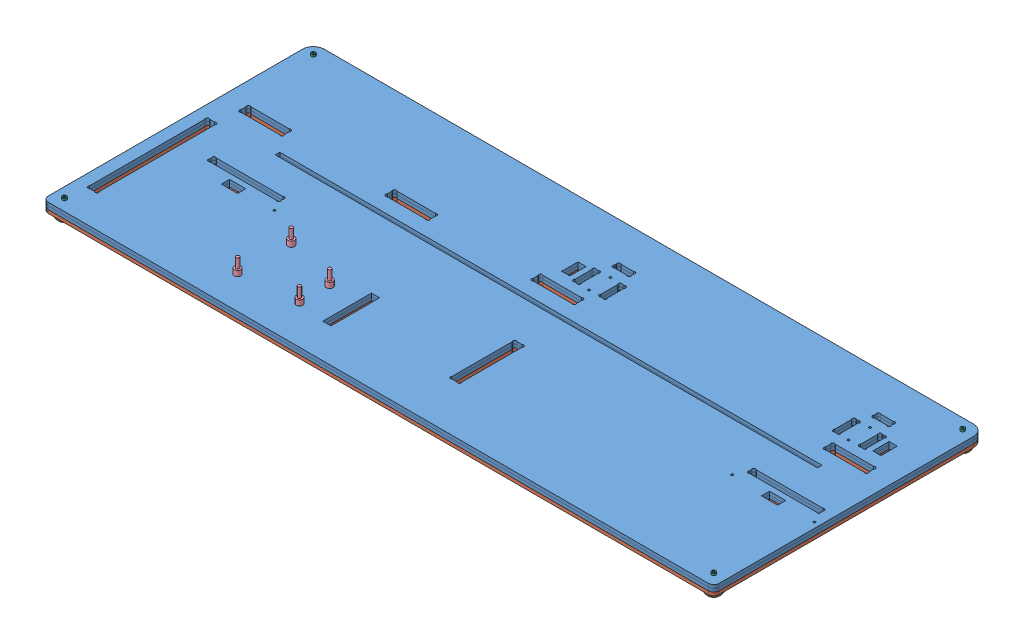
SolidWorks assembly socle-complet, configuration Défaut. Lengths in mm.
Overall size (621.62 30.74 251.62).
19 component instances, 6 part files, 46 mates.
Components (placement in the parent):
- socle-1-1: socle-1 [Défaut] at (-302.5453 40.1785 745) size (620 3 250)
- socle-1-2: socle-1 [Défaut] at (-302.5453 37.1785 745) size (620 3 250)
- socle-2-3: socle-2 [Défaut] at (-302.5453 34.1785 745) size (620 3 250)
- socle-patin-ecrou_m2-1: socle-patin-ecrou_m2 [Défaut] at (-292.5453 34.1785 735) x (0.367083 0 0.930188) z (-0.930188 0 0.367083) size (16 7.74 16)
- socle-patin-ecrou_m2-2: socle-patin-ecrou_m2 [Défaut] at (-292.5453 34.1785 505) x (-0.622025 0 0.782997) z (-0.782997 0 -0.622025) size (16 7.74 16)
- socle-patin-ecrou_m2-3: socle-patin-ecrou_m2 [Défaut] at (307.4547 34.1785 505) x (0.367083 0 0.930188) z (-0.930188 0 0.367083) size (16 7.74 16)
- socle-patin-ecrou_m2-4: socle-patin-ecrou_m2 [Défaut] at (307.4547 34.1785 735) x (0.367083 0 0.930188) z (-0.930188 0 0.367083) size (16 7.74 16)
- socle-carte_pied-1: socle-carte_pied [Défaut] at (-152.5453 38.1785 715) x (0 1 0) z (-0.920347 0 -0.391102) size (19 6 6)
- socle-carte_pied-2: socle-carte_pied [Défaut] at (-151.2753 38.1785 666.74) x (0 1 0) z (-0.842592 0 -0.538553) size (19 6 6)
- socle-carte_pied-3: socle-carte_pied [Défaut] at (-100.4753 38.1785 681.98) x (0 1 0) z (-0.819102 0 -0.573647) size (19 6 6)
- socle-carte_pied-4: socle-carte_pied [Défaut] at (-100.4753 38.1785 709.92) x (0 1 0) z (0.984574 0 0.174968) size (19 6 6)
- ecrou-h-1: ecrou-h [6007 HU M2] at (-292.5453 31.1785 735) size (4 1.6 4.62)
- vis-chc-1: vis-chc [Vis CHC M2x16] at (-292.5453 43.1785 735) x (0.999999 0 -0.001395) z (0.001395 0 0.999999) size (3.8 18 3.8)
- vis-chc-2: vis-chc [Vis CHC M2x16] at (307.4547 43.1785 735) x (0.999999 0 -0.001395) z (0.001395 0 0.999999) size (3.8 18 3.8)
- vis-chc-3: vis-chc [Vis CHC M2x16] at (-292.5453 43.1785 505) x (0.610012 0 -0.792392) z (0.792392 0 0.610012) size (3.8 18 3.8)
- vis-chc-4: vis-chc [Vis CHC M2x16] at (307.4547 43.1785 505) x (0.999999 0 -0.001395) z (0.001395 0 0.999999) size (3.8 18 3.8)
- ecrou-h-2: ecrou-h [6007 HU M2] at (307.4547 31.1785 735) size (4 1.6 4.62)
- ecrou-h-3: ecrou-h [6007 HU M2] at (307.4547 31.1785 505) size (4 1.6 4.62)
- ecrou-h-4: ecrou-h [6007 HU M2] at (-292.5453 31.1785 505) size (4 1.6 4.62)
Mates (geometry in assembly coordinates):
- Coïncidente1: coincident anti-aligned: plane of socle-1 through (-292.5453 40.1785 505) normal (0 -1 0); plane of socle-2 through (-292.5453 40.1785 505) normal (0 1 0)
- Coïncidente2: coincident aligned: plane of socle-1 through (-302.5453 43.1785 745) normal (0 0 1); plane of socle-2 through (-302.5453 40.1785 745) normal (0 0 1)
- Coïncidente3: coincident aligned: plane of socle-1 through (-302.5453 43.1785 505) normal (-1 0 0); plane of socle-2 through (-302.5453 40.1785 505) normal (-1 0 0)
- Coïncidente4: coincident anti-aligned: plane of socle-2 through (-292.5453 37.1785 505) normal (0 -1 0); plane of socle-3 through (-292.5453 37.1785 505) normal (0 1 0)
- Coïncidente5: coincident aligned: plane of socle-2 through (-302.5453 40.1785 745) normal (0 0 1); plane of socle-3 through (-302.5453 37.1785 745) normal (0 0 1)
- Coïncidente6: coincident aligned: plane of socle-2 through (-302.5453 40.1785 505) normal (-1 0 0); plane of socle-3 through (-302.5453 37.1785 505) normal (-1 0 0)
- Coaxiale1: concentric anti-aligned: cylinder of socle-3 through (-292.5453 37.1785 735) axis (0 -1 0) radius 1; cylinder of socle-patin-ecrou_m2-1 through (-292.5453 26.1785 735) axis (0 1 0) radius 1
- Coïncidente7: coincident anti-aligned: plane of socle-3 through (-292.5453 34.1785 505) normal (0 -1 0); plane of socle-patin-ecrou_m2-1 through (-295.482 34.1785 727.5585) normal (0 1 0)
- Coaxiale2: concentric anti-aligned: cylinder of socle-3 through (307.4547 37.1785 735) axis (0 -1 0) radius 1; cylinder of socle-patin-ecrou_m2-4 through (307.4547 26.1785 735) axis (0 1 0) radius 1
- Coaxiale3: concentric anti-aligned: cylinder of socle-3 through (307.4547 37.1785 505) axis (0 -1 0) radius 1; cylinder of socle-patin-ecrou_m2-3 through (307.4547 26.1785 505) axis (0 1 0) radius 1
- Coaxiale4: concentric anti-aligned: cylinder of socle-3 through (-292.5453 37.1785 505) axis (0 -1 0) radius 1; cylinder of socle-patin-ecrou_m2-2 through (-292.5453 26.1785 505) axis (0 1 0) radius 1
- Coïncidente8: coincident anti-aligned: plane of socle-3 through (-292.5453 34.1785 505) normal (0 -1 0); plane of socle-patin-ecrou_m2-2 through (-287.5691 34.1785 498.736) normal (0 1 0)
- Coïncidente9: coincident anti-aligned: plane of socle-3 through (-292.5453 34.1785 505) normal (0 -1 0); plane of socle-patin-ecrou_m2-3 through (304.518 34.1785 497.5585) normal (0 1 0)
- Coïncidente10: coincident anti-aligned: plane of socle-3 through (-292.5453 34.1785 505) normal (0 -1 0); plane of socle-patin-ecrou_m2-4 through (304.518 34.1785 727.5585) normal (0 1 0)
- Parallèle1: parallel anti-aligned: plane of socle-3 through (317.4547 37.1785 505) normal (1 0 0); plane of socle-patin-ecrou_m2-4 through (309.4725 26.2413 736.165) normal (-1 0 0)
- Parallèle2: parallel anti-aligned: plane of socle-3 through (317.4547 37.1785 505) normal (1 0 0); plane of socle-patin-ecrou_m2-3 through (309.4725 26.2413 506.165) normal (-1 0 0)
- Parallèle3: parallel anti-aligned: plane of socle-3 through (-302.5453 37.1785 505) normal (-1 0 0); plane of socle-patin-ecrou_m2-1 through (-294.5631 26.2413 733.835) normal (1 0 0)
- Parallèle4: parallel anti-aligned: plane of socle-3 through (-302.5453 37.1785 505) normal (-1 0 0); plane of socle-patin-ecrou_m2-2 through (-294.5631 26.2413 503.835) normal (1 0 0)
- Coaxiale5: concentric aligned: cylinder of socle-1 through (-152.5453 40.1785 715) axis (0 1 0) radius 1.59; cylinder of socle-carte_pied-1 through (-152.5453 57.1785 715) axis (0 1 0) radius 1.5
- Coaxiale6: concentric aligned: cylinder of socle-1 through (-100.4753 40.1785 709.92) axis (0 1 0) radius 1.59; cylinder of socle-carte_pied-4 through (-100.4753 57.1785 709.92) axis (0 1 0) radius 1.5
- Coaxiale7: concentric aligned: cylinder of socle-1 through (-100.4753 40.1785 681.98) axis (0 1 0) radius 1.59; cylinder of socle-carte_pied-3 through (-100.4753 57.1785 681.98) axis (0 1 0) radius 1.5
- Coaxiale8: concentric aligned: cylinder of socle-1 through (-151.2753 40.1785 666.74) axis (0 1 0) radius 1.59; cylinder of socle-carte_pied-2 through (-151.2753 57.1785 666.74) axis (0 1 0) radius 1.5
- Coïncidente11: coincident anti-aligned: plane of socle-1 through (-292.5453 43.1785 505) normal (0 1 0); plane of socle-carte_pied-1 through (-151.9586 43.1785 713.6195) normal (0 -1 0)
- Coïncidente12: coincident anti-aligned: plane of socle-1 through (-292.5453 43.1785 505) normal (0 1 0); plane of socle-carte_pied-2 through (-150.4675 43.1785 665.4761) normal (0 -1 0)
- Coïncidente13: coincident anti-aligned: plane of socle-1 through (-292.5453 43.1785 505) normal (0 1 0); plane of socle-carte_pied-3 through (-99.6148 43.1785 680.7513) normal (0 -1 0)
- Coïncidente14: coincident anti-aligned: plane of socle-1 through (-292.5453 43.1785 505) normal (0 1 0); plane of socle-carte_pied-4 through (-100.7378 43.1785 711.3969) normal (0 -1 0)
- Coaxiale9: concentric anti-aligned: cylinder of socle-1-1 through (-292.5453 43.1785 735) axis (0 -1 0) radius 1; cylinder of vis-chc-1 through (-292.5453 27.1785 735) axis (0 1 0) radius 1
- Coïncidente15: coincident anti-aligned: plane of socle-1-1 through (-292.5453 43.1785 505) normal (0 1 0); plane of vis-chc-1 through (-292.5453 43.1785 735) normal (0 -1 0)
- Coaxiale10: concentric aligned: cylinder of ecrou-h-1 through (-292.5453 29.5785 735) axis (0 1 0) radius 0.7835; cylinder of vis-chc-1 through (-292.5453 27.1785 735) axis (0 1 0) radius 1
- Parallèle5: parallel anti-aligned: plane of socle-patin-ecrou_m2-1 through (-292.5453 26.2413 732.67) normal (0.5 0 0.866025); plane of ecrou-h-1 through (-292.5453 29.5785 732.6906) normal (-0.5 0 -0.866025)
- Coïncidente18: coincident anti-aligned: plane of socle-patin-ecrou_m2-1 through (-292.5453 31.1785 735) normal (0 -1 0); plane of ecrou-h-1 through (-290.5453 31.1785 733.8453) normal (0 1 0)
- Coaxiale11: concentric anti-aligned: cylinder of socle-1-1 through (307.4547 43.1785 735) axis (0 -1 0) radius 1; cylinder of vis-chc-2 through (307.4547 27.1785 735) axis (0 1 0) radius 1
- Coïncidente19: coincident aligned: plane of socle-1-1 through (-292.5453 43.1785 505) normal (0 1 0); circle of vis-chc-2
- Coaxiale12: concentric anti-aligned: cylinder of socle-1-1 through (307.4547 43.1785 505) axis (0 -1 0) radius 1; cylinder of vis-chc-4 through (307.4547 27.1785 505) axis (0 1 0) radius 1
- Coïncidente20: coincident anti-aligned: plane of socle-1-1 through (-292.5453 43.1785 505) normal (0 1 0); plane of vis-chc-4 through (307.4547 43.1785 505) normal (0 -1 0)
- Coaxiale13: concentric anti-aligned: cylinder of socle-1-1 through (-292.5453 43.1785 505) axis (0 -1 0) radius 1; cylinder of vis-chc-3 through (-292.5453 27.1785 505) axis (0 1 0) radius 1
- Coïncidente21: coincident anti-aligned: plane of socle-1-1 through (-292.5453 43.1785 505) normal (0 1 0); plane of vis-chc-3 through (-292.5453 43.1785 505) normal (0 -1 0)
- Coïncidente22: coincident anti-aligned: plane of socle-patin-ecrou_m2-2 through (-292.5453 31.1785 505) normal (0 -1 0); plane of ecrou-h-4 through (-290.5453 31.1785 503.8453) normal (0 1 0)
- Parallèle10: parallel anti-aligned: plane of socle-patin-ecrou_m2-2 through (-294.5631 26.2413 506.165) normal (0.5 0 -0.866025); plane of ecrou-h-4 through (-294.5453 29.5785 506.1547) normal (-0.5 0 0.866025)
- Coaxiale20: concentric aligned: cylinder of vis-chc-3 through (-292.5453 27.1785 505) axis (0 1 0) radius 1; cylinder of ecrou-h-4 through (-292.5453 29.5785 505) axis (0 1 0) radius 0.7835
- Coïncidente28: coincident anti-aligned: plane of socle-patin-ecrou_m2-3 through (307.4547 31.1785 505) normal (0 -1 0); plane of ecrou-h-3 through (309.4547 31.1785 503.8453) normal (0 1 0)
- Parallèle11: parallel anti-aligned: plane of socle-patin-ecrou_m2-3 through (305.4369 26.2413 506.165) normal (0.5 0 -0.866025); plane of ecrou-h-3 through (305.4547 29.5785 506.1547) normal (-0.5 0 0.866025)
- Coaxiale21: concentric aligned: cylinder of vis-chc-4 through (307.4547 27.1785 505) axis (0 1 0) radius 1; cylinder of ecrou-h-3 through (307.4547 29.5785 505) axis (0 1 0) radius 0.7835
- Coïncidente30: coincident anti-aligned: plane of socle-patin-ecrou_m2-4 through (307.4547 31.1785 735) normal (0 -1 0); plane of ecrou-h-2 through (309.4547 31.1785 733.8453) normal (0 1 0)
- Parallèle13: parallel anti-aligned: plane of socle-patin-ecrou_m2-4 through (307.4547 26.2413 737.33) normal (-0.5 0 -0.866025); plane of ecrou-h-2 through (307.4547 29.5785 737.3094) normal (0.5 0 0.866025)
- Coaxiale23: concentric aligned: cylinder of vis-chc-2 through (307.4547 27.1785 735) axis (0 1 0) radius 1; cylinder of ecrou-h-2 through (307.4547 29.5785 735) axis (0 1 0) radius 0.7835
